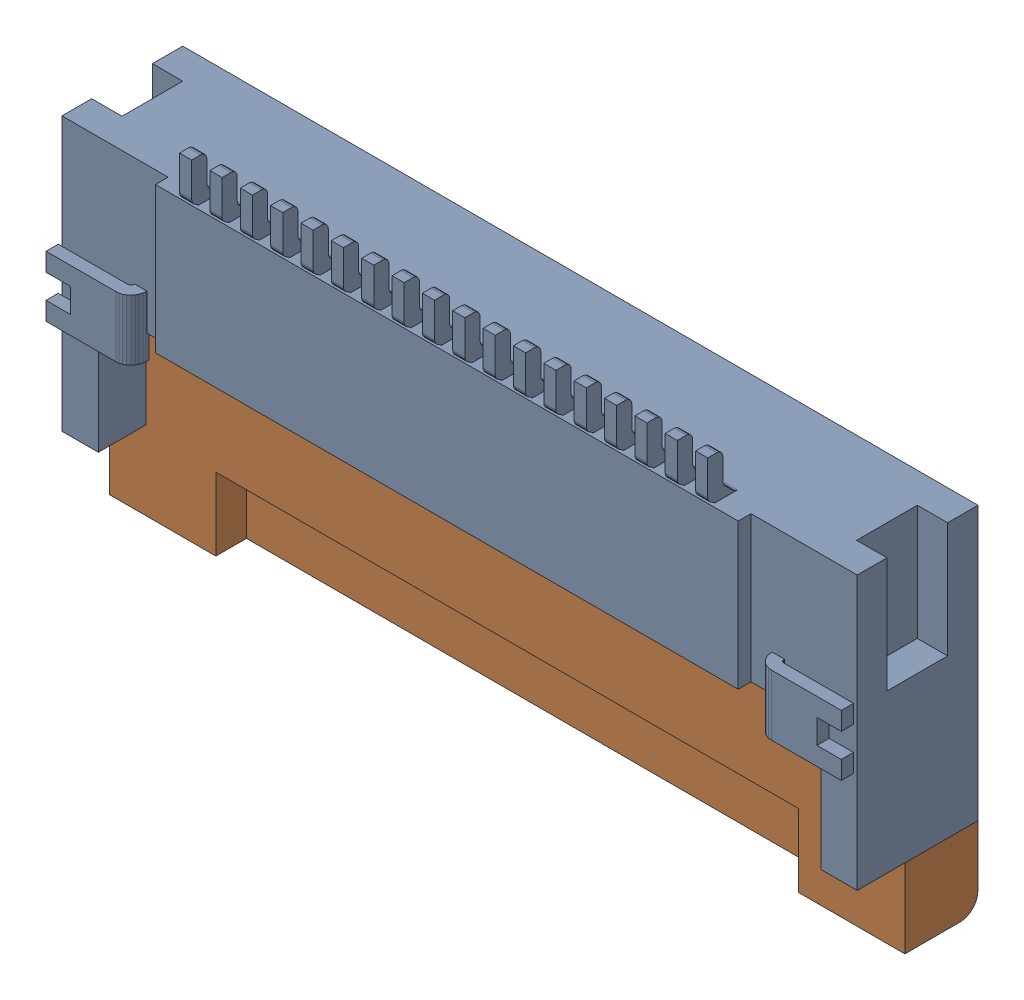
SolidWorks assembly CN1摄像头, configuration 默认. Lengths in mm.
Overall size (13.1 6.5 2.25).
2 component instances, 2 part files, 0 mates.
Components (placement in the parent):
- FPC-ZIF-SMD-Horizontal-0.5-18-1: FPC-ZIF-SMD-Horizontal-0.5-18 [默认] at (-0.0001 -9.0679 -0.3912) x (-1 0 0) z (0 -1 0) size (13.1 2.25 5.2)
- FPC-ZIF-SMD-Horizontal-0.5-18_2-1: FPC-ZIF-SMD-Horizontal-0.5-18_2 [默认] at (-0.0001 -9.0679 -0.3912) x (-1 0 0) z (0 -1 0) size (13.1 1.2 2.95)
